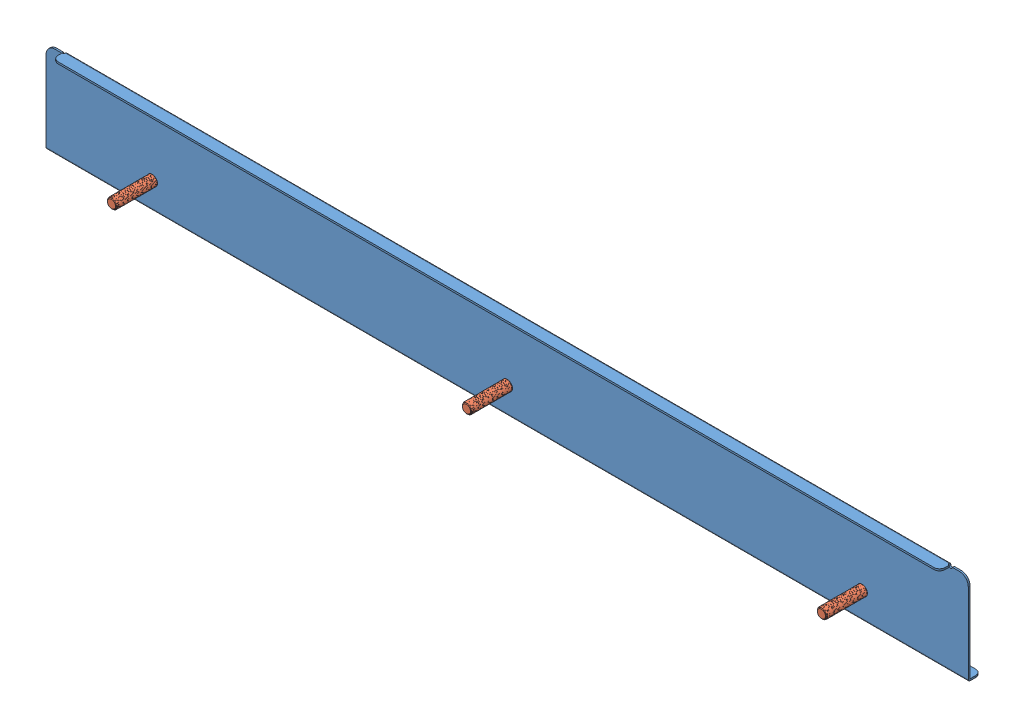
SolidWorks assembly 調風板, configuration 預設. Lengths in mm.
Overall size (825 83.2 48.49).
4 component instances, 2 part files, 2 mates.
Components (placement in the parent):
- FE2100LZ-54-26-1: FE2100LZ-54-26 [預設] at (-446.2276 -39.4948 -0.8) size (825 83.2 21.6)
- 備份 of 3分螺絲-1: 備份 of 3分螺絲 [預設] at (283.7724 -7.6948 -1.1) x (-0.923728 -0.383049 0) z (0.383049 -0.923728 0) size (16.17 44.79 14)
- 備份 of 3分螺絲-2: 備份 of 3分螺絲 [預設] at (-33.7276 -7.6948 -1.1) x (-0.923728 -0.383049 0) z (0.383049 -0.923728 0) size (16.17 44.79 14)
- 備份 of 3分螺絲-3: 備份 of 3分螺絲 [預設] at (-351.2276 -7.6948 -1.1) x (-0.923728 -0.383049 0) z (0.383049 -0.923728 0) size (16.17 44.79 14)
Mates (geometry in assembly coordinates):
- 重合/共線/共點1: coincident anti-aligned: plane of 備份 of 3分螺絲-1 through (283.7724 -7.6948 -0.8) normal (0 0 1); plane of FE2100LZ-54-26-1 through (-430.4776 50.5052 -0.8) normal (0 0 -1)
- 同軸心1: concentric aligned: cylinder of FE2100LZ-54-26-1 through (283.7724 -7.6948 0.8) axis (0 0 -1) radius 4.75; cylinder of 備份 of 3分螺絲-1 through (283.7724 -7.6948 -0.8) axis (0 0 -1) radius 6.25
